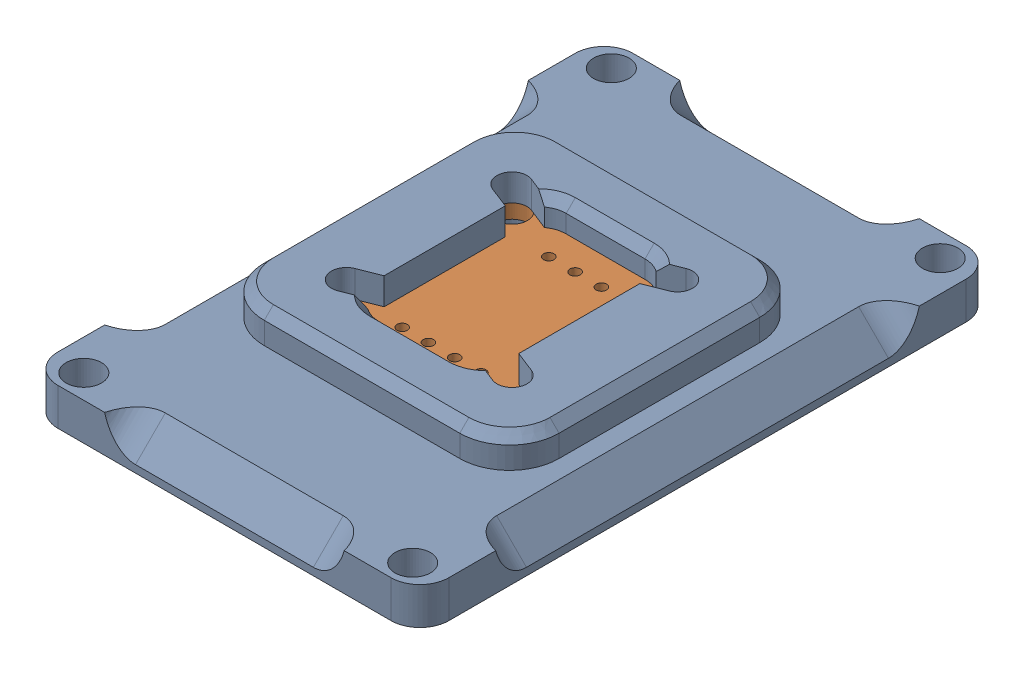
SolidWorks assembly Encoder_4__1, configuration Default. Lengths in mm.
Overall size (37.8 6.6 55.6).
2 component instances, 2 part files, 0 mates.
Components (placement in the parent):
- EncoderHousing_1-1: EncoderHousing_1 [Default] at (0 129.35 790) x (1 0 0) z (0 -1 0) size (37.8 55.6 6.6)
- AS5600_1-1: AS5600_1 [Default] at (0 131.65 790) x (1 0 0) z (0 0 -1) size (23 3.5 23)
